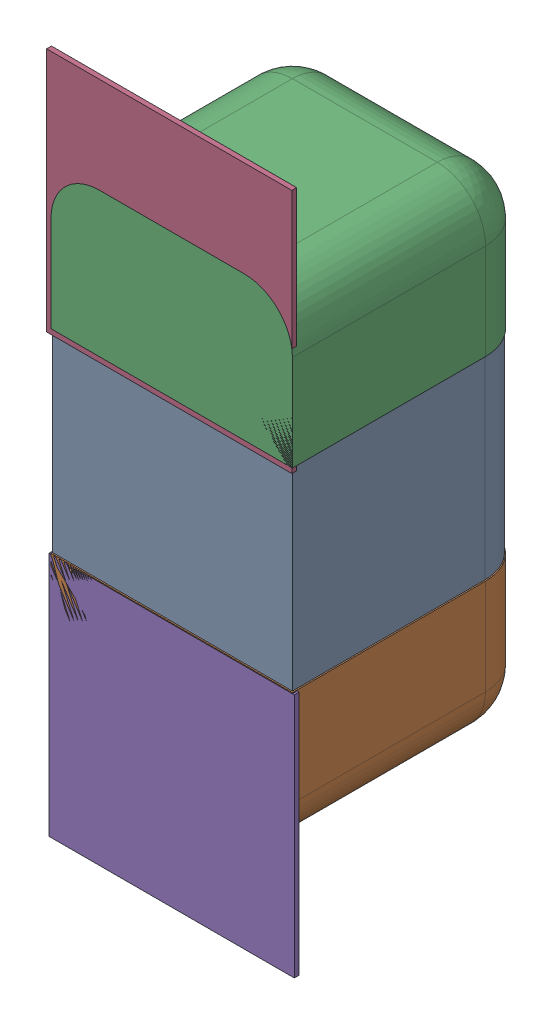
SolidWorks assembly C42, configuration Défaut. Lengths in mm.
Overall size (0.51 1.41 0.5).
8 component instances, 4 part files, 0 mates.
Components (placement in the parent):
- 6501210464-1: 6501210464 [Défaut] at (-2.7686 -20.028 -2.0818) x (0 1 0) z (-1 0 0) size (1 0.5 0.5)
  - Open CASCADE STEP translator 7.5 2.33.1.1-1: Open CASCADE STEP translator 7.5 2.33.1.1 [Défaut] at origin size (0.4 0.5 0.5)
  - Open CASCADE STEP translator 7.5 2.33.1.2-1: Open CASCADE STEP translator 7.5 2.33.1.2 [Défaut] at origin size (0.3 0.5 0.5)
  - Open CASCADE STEP translator 7.5 2.33.1.3-1: Open CASCADE STEP translator 7.5 2.33.1.3 [Défaut] at origin size (0.3 0.5 0.5)
- 6504207776-1: 6504207776 [Défaut] at (-2.7738 -19.583 -2.0918) size (0.51 0.51 0.01)
  - Extruded-1: Extruded [Défaut] at origin size (0.51 0.51 0.01)
- 6504207776-2: 6504207776 [Défaut] at (-2.7686 -20.4853 -2.0918) size (0.51 0.51 0.01)
  - Extruded-1: Extruded [Défaut] at origin size (0.51 0.51 0.01)
